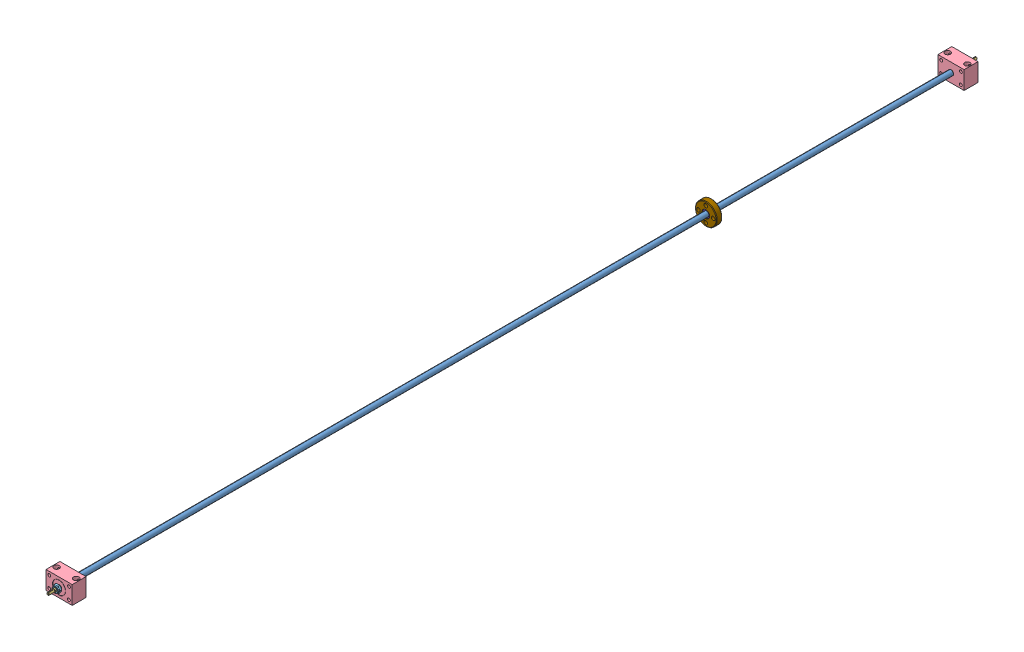
SolidWorks assembly 900_RA_EK_EK_1800_20900_FS, configuration Valor predeterminado. Lengths in mm.
Overall size (50.8 42 1799.55).
15 component instances, 9 part files, 7 mates.
Components (placement in the parent):
- Screw_900-RA-1: Screw_900-RA [Valor predeterminado] at origin size (10 10 1701)
- EndCode1_7-EK-1: EndCode1_7-EK [Valor predeterminado] at (0 0 1701) x (0 0 1) z (-1 0 0) size (49.28 35.05 50.8)
  - Place Holder-1: Place Holder [Valor predeterminado] at origin size (0.38 0.51 0.51)
  - EndMachining_7-3K-1: EndMachining_7-3K [Valor predeterminado] x (0 0 1) z (-1 0 0) size (7 7 49.28)
  - EZM_EZM-1007-1: EZM_EZM-1007 [Valor predeterminado] at (27.305 -17.4498 25.4) x (0 0 -1) z (1 0 0) size (50.8 35.05 26.92)
  - LockNut(1)_N-00.7-1: LockNut(1)_N-00.7 [Valor predeterminado] at (28.8798 0 0) x (1 0 0) z (0 0.998865 0.047634) size (7.05 16.48 14.68)
  - Spacer-1: Spacer [Valor predeterminado] at origin size (28.88 9.91 9.91)
- EndCode2_7-EK-1: EndCode2_7-EK [Valor predeterminado] x (0 0 -1) z (1 0 0) size (49.28 35.05 50.8)
  - Place Holder-1: Place Holder [Valor predeterminado] at origin size (0.38 0.51 0.51)
  - EndMachining_7-3K-1: EndMachining_7-3K [Valor predeterminado] x (0 0 1) z (-1 0 0) size (7 7 49.28)
  - EZM_EZM-1007-1: EZM_EZM-1007 [Valor predeterminado] at (27.305 -17.4498 25.4) x (0 0 -1) z (1 0 0) size (50.8 35.05 26.92)
  - LockNut(1)_N-00.7-1: LockNut(1)_N-00.7 [Valor predeterminado] at (28.8798 0 0) x (1 0 0) z (0 0.998865 0.047634) size (7.05 16.48 14.68)
  - Spacer2-1: Spacer2 [Valor predeterminado] at origin size (28.88 9.91 9.91)
- Nut_20900-1: Nut_20900 [Valor predeterminado] at (0 0 428.4213) x (-1 0 0) z (0 0 -1) size (18 18 16)
- Flange_72001-1: Flange_72001 [Valor predeterminado] at (0 0 474.8662) x (0 0 -1) z (1 0 0) size (11 42 42)
Mates (geometry in assembly coordinates):
- Concêntrico1: concentric aligned: cylinder of Screw_900-RA-1 through (0 0 1701) axis (0 0 -1) radius 5; cylinder of Nut_20900-1 through (0 0 457.8662) axis (0 0 -1) radius 4.5
- Concêntrico3: concentric anti-aligned: cylinder of Screw_900-RA-1 through (0 0 1701) axis (0 0 -1) radius 5; cylinder of Flange_72001-1 through (0 0 463.8662) axis (0 0 1) radius 7.5
- Coincidente1: coincident anti-aligned: plane of Nut_20900-1 through (0 9 463.8662) normal (0 0 1); plane of Flange_72001-1 through (0 0 463.8662) normal (0 0 -1)
- Coincidente5: coincident: plane of Screw_900-RA-1 through (0 0 1701) normal (0 0 1); plane of EndCode1_7-EK-1/EndMachining_7-3K-1 through (0 0 1701) normal (0 0 -1)
- Concêntrico6: concentric aligned: cylinder of Screw_900-RA-1 through (0 0 1701) axis (0 0 -1) radius 5; cylinder of EndCode1_7-EK-1/Spacer-1 through (0 0 1729.8798) axis (0 0 -1) radius 4.953
- Coincidente6: coincident: plane of Screw_900-RA-1 through (0 0 0) normal (0 0 -1); plane of EndCode2_7-EK-1/EndMachining_7-3K-1 through (0 0 0) normal (0 0 1)
- Concêntrico7: concentric anti-aligned: cylinder of Screw_900-RA-1 through (0 0 1701) axis (0 0 -1) radius 5; cylinder of EndCode2_7-EK-1/Spacer2-1 through (0 0 -28.8798) axis (0 0 1) radius 4.953
